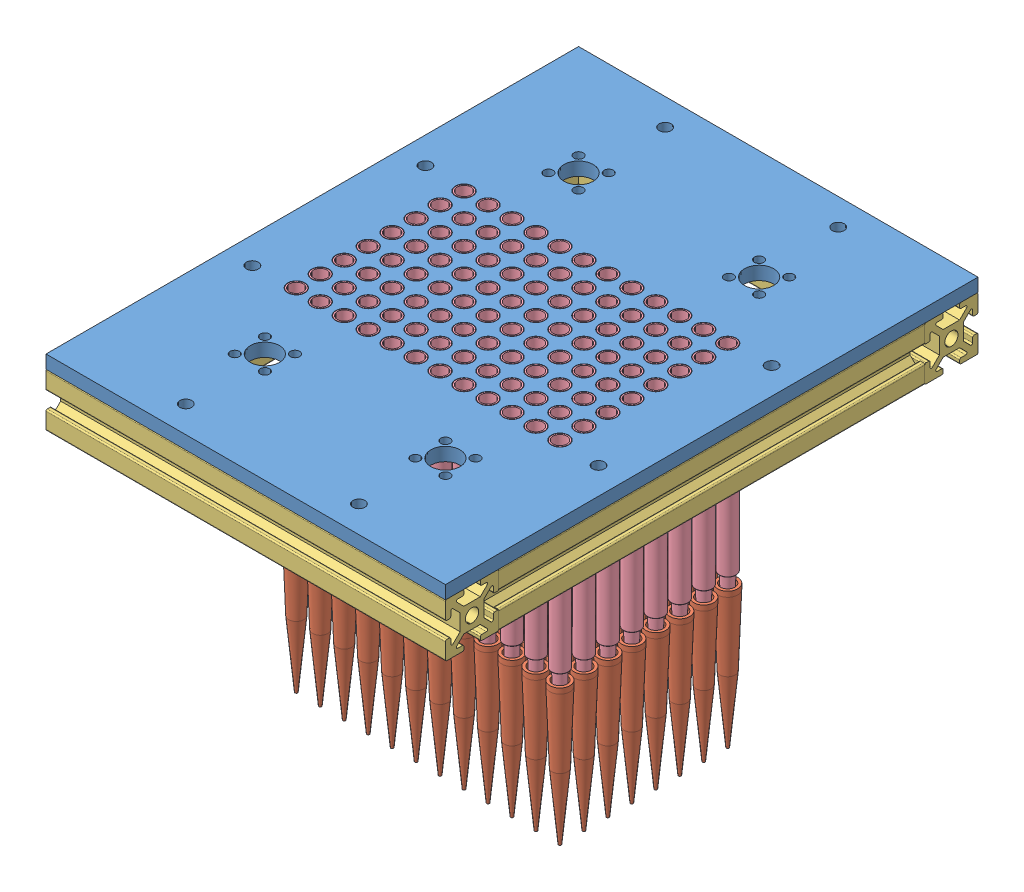
SolidWorks assembly pipette_plate_with_cylinders, configuration Standard. Lengths in mm.
Overall size (150 131.5 200).
197 component instances, 4 part files, 15 mates.
Components (placement in the parent):
- pipette_plate-1: pipette_plate [Standard] at origin size (150 5 200)
- pipette_tip-1: pipette_tip [Standard] at (-99 -73 -63) size (7.5 53.5 7.5)
- 20x20_extrude-1: 20x20_extrude [width3] at (15.5 -10 -111.5) size (20 20 160)
- 20x20_extrude-2: 20x20_extrude [width3] at (-114.5 -10 -111.5) size (20 20 160)
- 20x20_extrude-3: 20x20_extrude [width4_smaller] at (25.5 -10 58.5) x (0 0 1) z (-1 0 0) size (20 20 150)
- 20x20_extrude-4: 20x20_extrude [width4_smaller] at (25.5 -10 -121.5) x (0 0 1) z (-1 0 0) size (20 20 150)
- pipette_tip-2: pipette_tip [Standard] at (-90 -73 -63) size (7.5 53.5 7.5)
- pipette_tip-3: pipette_tip [Standard] at (-81 -73 -63) size (7.5 53.5 7.5)
- pipette_tip-4: pipette_tip [Standard] at (-72 -73 -63) size (7.5 53.5 7.5)
- pipette_tip-5: pipette_tip [Standard] at (-63 -73 -63) size (7.5 53.5 7.5)
- pipette_tip-6: pipette_tip [Standard] at (-54 -73 -63) size (7.5 53.5 7.5)
- pipette_tip-7: pipette_tip [Standard] at (-45 -73 -63) size (7.5 53.5 7.5)
- pipette_tip-8: pipette_tip [Standard] at (-36 -73 -63) size (7.5 53.5 7.5)
- pipette_tip-9: pipette_tip [Standard] at (-27 -73 -63) size (7.5 53.5 7.5)
- pipette_tip-10: pipette_tip [Standard] at (-18 -73 -63) size (7.5 53.5 7.5)
- pipette_tip-11: pipette_tip [Standard] at (-9 -73 -63) size (7.5 53.5 7.5)
- pipette_tip-12: pipette_tip [Standard] at (0 -73 -63) size (7.5 53.5 7.5)
- pipette_tip-13: pipette_tip [Standard] at (-99 -73 -54) size (7.5 53.5 7.5)
- pipette_tip-14: pipette_tip [Standard] at (-90 -73 -54) size (7.5 53.5 7.5)
- pipette_tip-15: pipette_tip [Standard] at (-81 -73 -54) size (7.5 53.5 7.5)
- pipette_tip-16: pipette_tip [Standard] at (-72 -73 -54) size (7.5 53.5 7.5)
- pipette_tip-17: pipette_tip [Standard] at (-63 -73 -54) size (7.5 53.5 7.5)
- pipette_tip-18: pipette_tip [Standard] at (-54 -73 -54) size (7.5 53.5 7.5)
- pipette_tip-19: pipette_tip [Standard] at (-45 -73 -54) size (7.5 53.5 7.5)
- pipette_tip-20: pipette_tip [Standard] at (-36 -73 -54) size (7.5 53.5 7.5)
- pipette_tip-21: pipette_tip [Standard] at (-27 -73 -54) size (7.5 53.5 7.5)
- pipette_tip-22: pipette_tip [Standard] at (-18 -73 -54) size (7.5 53.5 7.5)
- pipette_tip-23: pipette_tip [Standard] at (-9 -73 -54) size (7.5 53.5 7.5)
- pipette_tip-24: pipette_tip [Standard] at (0 -73 -54) size (7.5 53.5 7.5)
- pipette_tip-25: pipette_tip [Standard] at (-99 -73 -45) size (7.5 53.5 7.5)
- pipette_tip-26: pipette_tip [Standard] at (-90 -73 -45) size (7.5 53.5 7.5)
- pipette_tip-27: pipette_tip [Standard] at (-81 -73 -45) size (7.5 53.5 7.5)
- pipette_tip-28: pipette_tip [Standard] at (-72 -73 -45) size (7.5 53.5 7.5)
- pipette_tip-29: pipette_tip [Standard] at (-63 -73 -45) size (7.5 53.5 7.5)
- pipette_tip-30: pipette_tip [Standard] at (-54 -73 -45) size (7.5 53.5 7.5)
- pipette_tip-31: pipette_tip [Standard] at (-45 -73 -45) size (7.5 53.5 7.5)
- pipette_tip-32: pipette_tip [Standard] at (-36 -73 -45) size (7.5 53.5 7.5)
- pipette_tip-33: pipette_tip [Standard] at (-27 -73 -45) size (7.5 53.5 7.5)
- pipette_tip-34: pipette_tip [Standard] at (-18 -73 -45) size (7.5 53.5 7.5)
- pipette_tip-35: pipette_tip [Standard] at (-9 -73 -45) size (7.5 53.5 7.5)
- pipette_tip-36: pipette_tip [Standard] at (0 -73 -45) size (7.5 53.5 7.5)
- pipette_tip-37: pipette_tip [Standard] at (-99 -73 -36) size (7.5 53.5 7.5)
- pipette_tip-38: pipette_tip [Standard] at (-90 -73 -36) size (7.5 53.5 7.5)
- pipette_tip-39: pipette_tip [Standard] at (-81 -73 -36) size (7.5 53.5 7.5)
- pipette_tip-40: pipette_tip [Standard] at (-72 -73 -36) size (7.5 53.5 7.5)
- pipette_tip-41: pipette_tip [Standard] at (-63 -73 -36) size (7.5 53.5 7.5)
- pipette_tip-42: pipette_tip [Standard] at (-54 -73 -36) size (7.5 53.5 7.5)
- pipette_tip-43: pipette_tip [Standard] at (-45 -73 -36) size (7.5 53.5 7.5)
- pipette_tip-44: pipette_tip [Standard] at (-36 -73 -36) size (7.5 53.5 7.5)
- pipette_tip-45: pipette_tip [Standard] at (-27 -73 -36) size (7.5 53.5 7.5)
- pipette_tip-46: pipette_tip [Standard] at (-18 -73 -36) size (7.5 53.5 7.5)
- pipette_tip-47: pipette_tip [Standard] at (-9 -73 -36) size (7.5 53.5 7.5)
- pipette_tip-48: pipette_tip [Standard] at (0 -73 -36) size (7.5 53.5 7.5)
- pipette_tip-49: pipette_tip [Standard] at (-99 -73 -27) size (7.5 53.5 7.5)
- pipette_tip-50: pipette_tip [Standard] at (-90 -73 -27) size (7.5 53.5 7.5)
- pipette_tip-51: pipette_tip [Standard] at (-81 -73 -27) size (7.5 53.5 7.5)
- pipette_tip-52: pipette_tip [Standard] at (-72 -73 -27) size (7.5 53.5 7.5)
- pipette_tip-53: pipette_tip [Standard] at (-63 -73 -27) size (7.5 53.5 7.5)
- pipette_tip-54: pipette_tip [Standard] at (-54 -73 -27) size (7.5 53.5 7.5)
- pipette_tip-55: pipette_tip [Standard] at (-45 -73 -27) size (7.5 53.5 7.5)
- pipette_tip-56: pipette_tip [Standard] at (-36 -73 -27) size (7.5 53.5 7.5)
- pipette_tip-57: pipette_tip [Standard] at (-27 -73 -27) size (7.5 53.5 7.5)
- pipette_tip-58: pipette_tip [Standard] at (-18 -73 -27) size (7.5 53.5 7.5)
- pipette_tip-59: pipette_tip [Standard] at (-9 -73 -27) size (7.5 53.5 7.5)
- pipette_tip-60: pipette_tip [Standard] at (0 -73 -27) size (7.5 53.5 7.5)
- pipette_tip-61: pipette_tip [Standard] at (-99 -73 -18) size (7.5 53.5 7.5)
- pipette_tip-62: pipette_tip [Standard] at (-90 -73 -18) size (7.5 53.5 7.5)
- pipette_tip-63: pipette_tip [Standard] at (-81 -73 -18) size (7.5 53.5 7.5)
- pipette_tip-64: pipette_tip [Standard] at (-72 -73 -18) size (7.5 53.5 7.5)
- pipette_tip-65: pipette_tip [Standard] at (-63 -73 -18) size (7.5 53.5 7.5)
- pipette_tip-66: pipette_tip [Standard] at (-54 -73 -18) size (7.5 53.5 7.5)
- pipette_tip-67: pipette_tip [Standard] at (-45 -73 -18) size (7.5 53.5 7.5)
- pipette_tip-68: pipette_tip [Standard] at (-36 -73 -18) size (7.5 53.5 7.5)
- pipette_tip-69: pipette_tip [Standard] at (-27 -73 -18) size (7.5 53.5 7.5)
- pipette_tip-70: pipette_tip [Standard] at (-18 -73 -18) size (7.5 53.5 7.5)
- pipette_tip-71: pipette_tip [Standard] at (-9 -73 -18) size (7.5 53.5 7.5)
- pipette_tip-72: pipette_tip [Standard] at (0 -73 -18) size (7.5 53.5 7.5)
- pipette_tip-73: pipette_tip [Standard] at (-99 -73 -9) size (7.5 53.5 7.5)
- pipette_tip-74: pipette_tip [Standard] at (-90 -73 -9) size (7.5 53.5 7.5)
- pipette_tip-75: pipette_tip [Standard] at (-81 -73 -9) size (7.5 53.5 7.5)
- pipette_tip-76: pipette_tip [Standard] at (-72 -73 -9) size (7.5 53.5 7.5)
- pipette_tip-77: pipette_tip [Standard] at (-63 -73 -9) size (7.5 53.5 7.5)
- pipette_tip-78: pipette_tip [Standard] at (-54 -73 -9) size (7.5 53.5 7.5)
- pipette_tip-79: pipette_tip [Standard] at (-45 -73 -9) size (7.5 53.5 7.5)
- pipette_tip-80: pipette_tip [Standard] at (-36 -73 -9) size (7.5 53.5 7.5)
- pipette_tip-81: pipette_tip [Standard] at (-27 -73 -9) size (7.5 53.5 7.5)
- pipette_tip-82: pipette_tip [Standard] at (-18 -73 -9) size (7.5 53.5 7.5)
- pipette_tip-83: pipette_tip [Standard] at (-9 -73 -9) size (7.5 53.5 7.5)
- pipette_tip-84: pipette_tip [Standard] at (0 -73 -9) size (7.5 53.5 7.5)
- pipette_tip-85: pipette_tip [Standard] at (-99 -73 0) size (7.5 53.5 7.5)
- pipette_tip-86: pipette_tip [Standard] at (-90 -73 0) size (7.5 53.5 7.5)
- pipette_tip-87: pipette_tip [Standard] at (-81 -73 0) size (7.5 53.5 7.5)
- pipette_tip-88: pipette_tip [Standard] at (-72 -73 0) size (7.5 53.5 7.5)
- pipette_tip-89: pipette_tip [Standard] at (-63 -73 0) size (7.5 53.5 7.5)
- pipette_tip-90: pipette_tip [Standard] at (-54 -73 0) size (7.5 53.5 7.5)
- pipette_tip-91: pipette_tip [Standard] at (-45 -73 0) size (7.5 53.5 7.5)
- pipette_tip-92: pipette_tip [Standard] at (-36 -73 0) size (7.5 53.5 7.5)
- pipette_tip-93: pipette_tip [Standard] at (-27 -73 0) size (7.5 53.5 7.5)
- pipette_tip-94: pipette_tip [Standard] at (-18 -73 0) size (7.5 53.5 7.5)
- pipette_tip-95: pipette_tip [Standard] at (-9 -73 0) size (7.5 53.5 7.5)
- pipette_tip-96: pipette_tip [Standard] at (0 -73 0) size (7.5 53.5 7.5)
- 1ml syringe barrel-1: 1ml syringe barrel [Standard] at (-99 -77.5 -63) x (0.980653 0 -0.195756) z (0.195756 0 0.980653) size (6.2 82.5 6.2)
- 1ml syringe barrel-2: 1ml syringe barrel [Standard] at (-90 -77.5 -63) x (0.980653 0 -0.195756) z (0.195756 0 0.980653) size (6.2 82.5 6.2)
- 1ml syringe barrel-3: 1ml syringe barrel [Standard] at (-81 -77.5 -63) x (0.980653 0 -0.195756) z (0.195756 0 0.980653) size (6.2 82.5 6.2)
- 1ml syringe barrel-4: 1ml syringe barrel [Standard] at (-72 -77.5 -63) x (0.980653 0 -0.195756) z (0.195756 0 0.980653) size (6.2 82.5 6.2)
- 1ml syringe barrel-5: 1ml syringe barrel [Standard] at (-63 -77.5 -63) x (0.980653 0 -0.195756) z (0.195756 0 0.980653) size (6.2 82.5 6.2)
- 1ml syringe barrel-6: 1ml syringe barrel [Standard] at (-54 -77.5 -63) x (0.980653 0 -0.195756) z (0.195756 0 0.980653) size (6.2 82.5 6.2)
- 1ml syringe barrel-7: 1ml syringe barrel [Standard] at (-45 -77.5 -63) x (0.980653 0 -0.195756) z (0.195756 0 0.980653) size (6.2 82.5 6.2)
- 1ml syringe barrel-8: 1ml syringe barrel [Standard] at (-36 -77.5 -63) x (0.980653 0 -0.195756) z (0.195756 0 0.980653) size (6.2 82.5 6.2)
- 1ml syringe barrel-9: 1ml syringe barrel [Standard] at (-27 -77.5 -63) x (0.980653 0 -0.195756) z (0.195756 0 0.980653) size (6.2 82.5 6.2)
- 1ml syringe barrel-10: 1ml syringe barrel [Standard] at (-18 -77.5 -63) x (0.980653 0 -0.195756) z (0.195756 0 0.980653) size (6.2 82.5 6.2)
- 1ml syringe barrel-11: 1ml syringe barrel [Standard] at (-9 -77.5 -63) x (0.980653 0 -0.195756) z (0.195756 0 0.980653) size (6.2 82.5 6.2)
- 1ml syringe barrel-12: 1ml syringe barrel [Standard] at (0 -77.5 -63) x (0.980653 0 -0.195756) z (0.195756 0 0.980653) size (6.2 82.5 6.2)
- 1ml syringe barrel-13: 1ml syringe barrel [Standard] at (-99 -77.5 -54) x (0.980653 0 -0.195756) z (0.195756 0 0.980653) size (6.2 82.5 6.2)
- 1ml syringe barrel-14: 1ml syringe barrel [Standard] at (-90 -77.5 -54) x (0.980653 0 -0.195756) z (0.195756 0 0.980653) size (6.2 82.5 6.2)
- 1ml syringe barrel-15: 1ml syringe barrel [Standard] at (-81 -77.5 -54) x (0.980653 0 -0.195756) z (0.195756 0 0.980653) size (6.2 82.5 6.2)
- 1ml syringe barrel-16: 1ml syringe barrel [Standard] at (-72 -77.5 -54) x (0.980653 0 -0.195756) z (0.195756 0 0.980653) size (6.2 82.5 6.2)
- 1ml syringe barrel-17: 1ml syringe barrel [Standard] at (-63 -77.5 -54) x (0.980653 0 -0.195756) z (0.195756 0 0.980653) size (6.2 82.5 6.2)
- 1ml syringe barrel-18: 1ml syringe barrel [Standard] at (-54 -77.5 -54) x (0.980653 0 -0.195756) z (0.195756 0 0.980653) size (6.2 82.5 6.2)
- 1ml syringe barrel-19: 1ml syringe barrel [Standard] at (-45 -77.5 -54) x (0.980653 0 -0.195756) z (0.195756 0 0.980653) size (6.2 82.5 6.2)
- 1ml syringe barrel-20: 1ml syringe barrel [Standard] at (-36 -77.5 -54) x (0.980653 0 -0.195756) z (0.195756 0 0.980653) size (6.2 82.5 6.2)
- 1ml syringe barrel-21: 1ml syringe barrel [Standard] at (-27 -77.5 -54) x (0.980653 0 -0.195756) z (0.195756 0 0.980653) size (6.2 82.5 6.2)
- 1ml syringe barrel-22: 1ml syringe barrel [Standard] at (-18 -77.5 -54) x (0.980653 0 -0.195756) z (0.195756 0 0.980653) size (6.2 82.5 6.2)
- 1ml syringe barrel-23: 1ml syringe barrel [Standard] at (-9 -77.5 -54) x (0.980653 0 -0.195756) z (0.195756 0 0.980653) size (6.2 82.5 6.2)
- 1ml syringe barrel-24: 1ml syringe barrel [Standard] at (0 -77.5 -54) x (0.980653 0 -0.195756) z (0.195756 0 0.980653) size (6.2 82.5 6.2)
- 1ml syringe barrel-25: 1ml syringe barrel [Standard] at (-99 -77.5 -45) x (0.980653 0 -0.195756) z (0.195756 0 0.980653) size (6.2 82.5 6.2)
- 1ml syringe barrel-26: 1ml syringe barrel [Standard] at (-90 -77.5 -45) x (0.980653 0 -0.195756) z (0.195756 0 0.980653) size (6.2 82.5 6.2)
- 1ml syringe barrel-27: 1ml syringe barrel [Standard] at (-81 -77.5 -45) x (0.980653 0 -0.195756) z (0.195756 0 0.980653) size (6.2 82.5 6.2)
- 1ml syringe barrel-28: 1ml syringe barrel [Standard] at (-72 -77.5 -45) x (0.980653 0 -0.195756) z (0.195756 0 0.980653) size (6.2 82.5 6.2)
- 1ml syringe barrel-29: 1ml syringe barrel [Standard] at (-63 -77.5 -45) x (0.980653 0 -0.195756) z (0.195756 0 0.980653) size (6.2 82.5 6.2)
- 1ml syringe barrel-30: 1ml syringe barrel [Standard] at (-54 -77.5 -45) x (0.980653 0 -0.195756) z (0.195756 0 0.980653) size (6.2 82.5 6.2)
- 1ml syringe barrel-31: 1ml syringe barrel [Standard] at (-45 -77.5 -45) x (0.980653 0 -0.195756) z (0.195756 0 0.980653) size (6.2 82.5 6.2)
- 1ml syringe barrel-32: 1ml syringe barrel [Standard] at (-36 -77.5 -45) x (0.980653 0 -0.195756) z (0.195756 0 0.980653) size (6.2 82.5 6.2)
- 1ml syringe barrel-33: 1ml syringe barrel [Standard] at (-27 -77.5 -45) x (0.980653 0 -0.195756) z (0.195756 0 0.980653) size (6.2 82.5 6.2)
- 1ml syringe barrel-34: 1ml syringe barrel [Standard] at (-18 -77.5 -45) x (0.980653 0 -0.195756) z (0.195756 0 0.980653) size (6.2 82.5 6.2)
- 1ml syringe barrel-35: 1ml syringe barrel [Standard] at (-9 -77.5 -45) x (0.980653 0 -0.195756) z (0.195756 0 0.980653) size (6.2 82.5 6.2)
- 1ml syringe barrel-36: 1ml syringe barrel [Standard] at (0 -77.5 -45) x (0.980653 0 -0.195756) z (0.195756 0 0.980653) size (6.2 82.5 6.2)
- 1ml syringe barrel-37: 1ml syringe barrel [Standard] at (-99 -77.5 -36) x (0.980653 0 -0.195756) z (0.195756 0 0.980653) size (6.2 82.5 6.2)
- 1ml syringe barrel-38: 1ml syringe barrel [Standard] at (-90 -77.5 -36) x (0.980653 0 -0.195756) z (0.195756 0 0.980653) size (6.2 82.5 6.2)
- 1ml syringe barrel-39: 1ml syringe barrel [Standard] at (-81 -77.5 -36) x (0.980653 0 -0.195756) z (0.195756 0 0.980653) size (6.2 82.5 6.2)
- 1ml syringe barrel-40: 1ml syringe barrel [Standard] at (-72 -77.5 -36) x (0.980653 0 -0.195756) z (0.195756 0 0.980653) size (6.2 82.5 6.2)
- 1ml syringe barrel-41: 1ml syringe barrel [Standard] at (-63 -77.5 -36) x (0.980653 0 -0.195756) z (0.195756 0 0.980653) size (6.2 82.5 6.2)
- 1ml syringe barrel-42: 1ml syringe barrel [Standard] at (-54 -77.5 -36) x (0.980653 0 -0.195756) z (0.195756 0 0.980653) size (6.2 82.5 6.2)
- 1ml syringe barrel-43: 1ml syringe barrel [Standard] at (-45 -77.5 -36) x (0.980653 0 -0.195756) z (0.195756 0 0.980653) size (6.2 82.5 6.2)
- 1ml syringe barrel-44: 1ml syringe barrel [Standard] at (-36 -77.5 -36) x (0.980653 0 -0.195756) z (0.195756 0 0.980653) size (6.2 82.5 6.2)
- 1ml syringe barrel-45: 1ml syringe barrel [Standard] at (-27 -77.5 -36) x (0.980653 0 -0.195756) z (0.195756 0 0.980653) size (6.2 82.5 6.2)
- 1ml syringe barrel-46: 1ml syringe barrel [Standard] at (-18 -77.5 -36) x (0.980653 0 -0.195756) z (0.195756 0 0.980653) size (6.2 82.5 6.2)
- 1ml syringe barrel-47: 1ml syringe barrel [Standard] at (-9 -77.5 -36) x (0.980653 0 -0.195756) z (0.195756 0 0.980653) size (6.2 82.5 6.2)
- 1ml syringe barrel-48: 1ml syringe barrel [Standard] at (0 -77.5 -36) x (0.980653 0 -0.195756) z (0.195756 0 0.980653) size (6.2 82.5 6.2)
- 1ml syringe barrel-49: 1ml syringe barrel [Standard] at (-99 -77.5 -27) x (0.980653 0 -0.195756) z (0.195756 0 0.980653) size (6.2 82.5 6.2)
- 1ml syringe barrel-50: 1ml syringe barrel [Standard] at (-90 -77.5 -27) x (0.980653 0 -0.195756) z (0.195756 0 0.980653) size (6.2 82.5 6.2)
- 1ml syringe barrel-51: 1ml syringe barrel [Standard] at (-81 -77.5 -27) x (0.980653 0 -0.195756) z (0.195756 0 0.980653) size (6.2 82.5 6.2)
- 1ml syringe barrel-52: 1ml syringe barrel [Standard] at (-72 -77.5 -27) x (0.980653 0 -0.195756) z (0.195756 0 0.980653) size (6.2 82.5 6.2)
- 1ml syringe barrel-53: 1ml syringe barrel [Standard] at (-63 -77.5 -27) x (0.980653 0 -0.195756) z (0.195756 0 0.980653) size (6.2 82.5 6.2)
- 1ml syringe barrel-54: 1ml syringe barrel [Standard] at (-54 -77.5 -27) x (0.980653 0 -0.195756) z (0.195756 0 0.980653) size (6.2 82.5 6.2)
- 1ml syringe barrel-55: 1ml syringe barrel [Standard] at (-45 -77.5 -27) x (0.980653 0 -0.195756) z (0.195756 0 0.980653) size (6.2 82.5 6.2)
- 1ml syringe barrel-56: 1ml syringe barrel [Standard] at (-36 -77.5 -27) x (0.980653 0 -0.195756) z (0.195756 0 0.980653) size (6.2 82.5 6.2)
- 1ml syringe barrel-57: 1ml syringe barrel [Standard] at (-27 -77.5 -27) x (0.980653 0 -0.195756) z (0.195756 0 0.980653) size (6.2 82.5 6.2)
- 1ml syringe barrel-58: 1ml syringe barrel [Standard] at (-18 -77.5 -27) x (0.980653 0 -0.195756) z (0.195756 0 0.980653) size (6.2 82.5 6.2)
- 1ml syringe barrel-59: 1ml syringe barrel [Standard] at (-9 -77.5 -27) x (0.980653 0 -0.195756) z (0.195756 0 0.980653) size (6.2 82.5 6.2)
- 1ml syringe barrel-60: 1ml syringe barrel [Standard] at (0 -77.5 -27) x (0.980653 0 -0.195756) z (0.195756 0 0.980653) size (6.2 82.5 6.2)
- 1ml syringe barrel-61: 1ml syringe barrel [Standard] at (-99 -77.5 -18) x (0.980653 0 -0.195756) z (0.195756 0 0.980653) size (6.2 82.5 6.2)
- 1ml syringe barrel-62: 1ml syringe barrel [Standard] at (-90 -77.5 -18) x (0.980653 0 -0.195756) z (0.195756 0 0.980653) size (6.2 82.5 6.2)
- 1ml syringe barrel-63: 1ml syringe barrel [Standard] at (-81 -77.5 -18) x (0.980653 0 -0.195756) z (0.195756 0 0.980653) size (6.2 82.5 6.2)
- 1ml syringe barrel-64: 1ml syringe barrel [Standard] at (-72 -77.5 -18) x (0.980653 0 -0.195756) z (0.195756 0 0.980653) size (6.2 82.5 6.2)
- 1ml syringe barrel-65: 1ml syringe barrel [Standard] at (-63 -77.5 -18) x (0.980653 0 -0.195756) z (0.195756 0 0.980653) size (6.2 82.5 6.2)
- 1ml syringe barrel-66: 1ml syringe barrel [Standard] at (-54 -77.5 -18) x (0.980653 0 -0.195756) z (0.195756 0 0.980653) size (6.2 82.5 6.2)
- 1ml syringe barrel-67: 1ml syringe barrel [Standard] at (-45 -77.5 -18) x (0.980653 0 -0.195756) z (0.195756 0 0.980653) size (6.2 82.5 6.2)
- 1ml syringe barrel-68: 1ml syringe barrel [Standard] at (-36 -77.5 -18) x (0.980653 0 -0.195756) z (0.195756 0 0.980653) size (6.2 82.5 6.2)
- 1ml syringe barrel-69: 1ml syringe barrel [Standard] at (-27 -77.5 -18) x (0.980653 0 -0.195756) z (0.195756 0 0.980653) size (6.2 82.5 6.2)
- 1ml syringe barrel-70: 1ml syringe barrel [Standard] at (-18 -77.5 -18) x (0.980653 0 -0.195756) z (0.195756 0 0.980653) size (6.2 82.5 6.2)
- 1ml syringe barrel-71: 1ml syringe barrel [Standard] at (-9 -77.5 -18) x (0.980653 0 -0.195756) z (0.195756 0 0.980653) size (6.2 82.5 6.2)
- 1ml syringe barrel-72: 1ml syringe barrel [Standard] at (0 -77.5 -18) x (0.980653 0 -0.195756) z (0.195756 0 0.980653) size (6.2 82.5 6.2)
- 1ml syringe barrel-73: 1ml syringe barrel [Standard] at (-99 -77.5 -9) x (0.980653 0 -0.195756) z (0.195756 0 0.980653) size (6.2 82.5 6.2)
- 1ml syringe barrel-74: 1ml syringe barrel [Standard] at (-90 -77.5 -9) x (0.980653 0 -0.195756) z (0.195756 0 0.980653) size (6.2 82.5 6.2)
- 1ml syringe barrel-75: 1ml syringe barrel [Standard] at (-81 -77.5 -9) x (0.980653 0 -0.195756) z (0.195756 0 0.980653) size (6.2 82.5 6.2)
- 1ml syringe barrel-76: 1ml syringe barrel [Standard] at (-72 -77.5 -9) x (0.980653 0 -0.195756) z (0.195756 0 0.980653) size (6.2 82.5 6.2)
- 1ml syringe barrel-77: 1ml syringe barrel [Standard] at (-63 -77.5 -9) x (0.980653 0 -0.195756) z (0.195756 0 0.980653) size (6.2 82.5 6.2)
- 1ml syringe barrel-78: 1ml syringe barrel [Standard] at (-54 -77.5 -9) x (0.980653 0 -0.195756) z (0.195756 0 0.980653) size (6.2 82.5 6.2)
- 1ml syringe barrel-79: 1ml syringe barrel [Standard] at (-45 -77.5 -9) x (0.980653 0 -0.195756) z (0.195756 0 0.980653) size (6.2 82.5 6.2)
- 1ml syringe barrel-80: 1ml syringe barrel [Standard] at (-36 -77.5 -9) x (0.980653 0 -0.195756) z (0.195756 0 0.980653) size (6.2 82.5 6.2)
- 1ml syringe barrel-81: 1ml syringe barrel [Standard] at (-27 -77.5 -9) x (0.980653 0 -0.195756) z (0.195756 0 0.980653) size (6.2 82.5 6.2)
- 1ml syringe barrel-82: 1ml syringe barrel [Standard] at (-18 -77.5 -9) x (0.980653 0 -0.195756) z (0.195756 0 0.980653) size (6.2 82.5 6.2)
- 1ml syringe barrel-83: 1ml syringe barrel [Standard] at (-9 -77.5 -9) x (0.980653 0 -0.195756) z (0.195756 0 0.980653) size (6.2 82.5 6.2)
- 1ml syringe barrel-84: 1ml syringe barrel [Standard] at (0 -77.5 -9) x (0.980653 0 -0.195756) z (0.195756 0 0.980653) size (6.2 82.5 6.2)
- 1ml syringe barrel-85: 1ml syringe barrel [Standard] at (-99 -77.5 0) x (0.980653 0 -0.195756) z (0.195756 0 0.980653) size (6.2 82.5 6.2)
- 1ml syringe barrel-86: 1ml syringe barrel [Standard] at (-90 -77.5 0) x (0.980653 0 -0.195756) z (0.195756 0 0.980653) size (6.2 82.5 6.2)
- 1ml syringe barrel-87: 1ml syringe barrel [Standard] at (-81 -77.5 0) x (0.980653 0 -0.195756) z (0.195756 0 0.980653) size (6.2 82.5 6.2)
- 1ml syringe barrel-88: 1ml syringe barrel [Standard] at (-72 -77.5 0) x (0.980653 0 -0.195756) z (0.195756 0 0.980653) size (6.2 82.5 6.2)
- 1ml syringe barrel-89: 1ml syringe barrel [Standard] at (-63 -77.5 0) x (0.980653 0 -0.195756) z (0.195756 0 0.980653) size (6.2 82.5 6.2)
- 1ml syringe barrel-90: 1ml syringe barrel [Standard] at (-54 -77.5 0) x (0.980653 0 -0.195756) z (0.195756 0 0.980653) size (6.2 82.5 6.2)
- 1ml syringe barrel-91: 1ml syringe barrel [Standard] at (-45 -77.5 0) x (0.980653 0 -0.195756) z (0.195756 0 0.980653) size (6.2 82.5 6.2)
- 1ml syringe barrel-92: 1ml syringe barrel [Standard] at (-36 -77.5 0) x (0.980653 0 -0.195756) z (0.195756 0 0.980653) size (6.2 82.5 6.2)
- 1ml syringe barrel-93: 1ml syringe barrel [Standard] at (-27 -77.5 0) x (0.980653 0 -0.195756) z (0.195756 0 0.980653) size (6.2 82.5 6.2)
- 1ml syringe barrel-94: 1ml syringe barrel [Standard] at (-18 -77.5 0) x (0.980653 0 -0.195756) z (0.195756 0 0.980653) size (6.2 82.5 6.2)
- 1ml syringe barrel-95: 1ml syringe barrel [Standard] at (-9 -77.5 0) x (0.980653 0 -0.195756) z (0.195756 0 0.980653) size (6.2 82.5 6.2)
- 1ml syringe barrel-96: 1ml syringe barrel [Standard] at (0 -77.5 0) x (0.980653 0 -0.195756) z (0.195756 0 0.980653) size (6.2 82.5 6.2)
Mates (geometry in assembly coordinates):
- Deckungsgleich1: coordinate: point of pipette_plate-1
- Deckungsgleich11: coincident anti-aligned: plane of pipette_plate-1 through (-48.25 0 -54) normal (0 -1 0); plane of 20x20_extrude-1 through (5.5 0 48.5) normal (0 1 0)
- Deckungsgleich12: coincident anti-aligned: plane of pipette_plate-1 through (-48.25 0 -54) normal (0 -1 0); plane of 20x20_extrude-2 through (-124.5 0 48.5) normal (0 1 0)
- Deckungsgleich13: coincident anti-aligned: plane of pipette_plate-1 through (-48.25 0 -54) normal (0 -1 0); plane of 20x20_extrude-3 through (-124.5 0 48.5) normal (0 1 0)
- Deckungsgleich14: coincident anti-aligned: plane of pipette_plate-1 through (-48.25 0 -54) normal (0 -1 0); plane of 20x20_extrude-4 through (-124.5 0 -131.5) normal (0 1 0)
- Deckungsgleich15: coincident aligned: plane of pipette_plate-1 through (4.5 -125.5388 -131.5) normal (0 0 -1); plane of 20x20_extrude-4 through (-124.5 -20 -131.5) normal (0 0 -1)
- Deckungsgleich16: coincident aligned: plane of pipette_plate-1 through (-124.5 -201.0995 -131.5) normal (-1 0 0); plane of 20x20_extrude-2 through (-124.5 -6.9 48.5) normal (-1 0 0)
- Deckungsgleich19: coincident aligned: plane of pipette_plate-1 through (25.5 -201.0995 -131.5) normal (1 0 0); plane of 20x20_extrude-1 through (25.5 0 48.5) normal (1 0 0)
- Deckungsgleich23: coincident aligned: plane of pipette_plate-1 through (25.5 -201.0995 -131.5) normal (1 0 0); plane of 20x20_extrude-4 through (25.5 -10 -121.5) normal (1 0 0)
- Deckungsgleich24: coincident anti-aligned: plane of 20x20_extrude-1 through (15.5 -10 -111.5) normal (0 0 -1); plane of 20x20_extrude-4 through (-124.5 -13.1 -111.5) normal (0 0 1)
- Deckungsgleich25: coincident aligned: plane of pipette_plate-1 through (25.5 -201.0995 -131.5) normal (1 0 0); plane of 20x20_extrude-3 through (25.5 -10 58.5) normal (1 0 0)
- Deckungsgleich26: coincident aligned: plane of pipette_plate-1 through (4.5 -125.5388 68.5) normal (0 0 1); plane of 20x20_extrude-3 through (-124.5 0 68.5) normal (0 0 1)
- Deckungsgleich27: coincident anti-aligned: plane of 20x20_extrude-2 through (-114.5 -10 -111.5) normal (0 0 -1); plane of 20x20_extrude-4 through (-124.5 -13.1 -111.5) normal (0 0 1)
- Konzentrisch7: concentric anti-aligned: cylinder of pipette_plate-1 through (-99 0 -63) axis (0 -1 0) radius 3.25; cylinder of 1ml syringe barrel-1 through (-99 -77.5 -63) axis (0 1 0) radius 3.1
- Deckungsgleich38: coincident aligned: plane of pipette_plate-1 through (-48.25 5 -54) normal (0 1 0); plane of 1ml syringe barrel-1 through (-101.5497 5 -62.491) normal (0 1 0)
